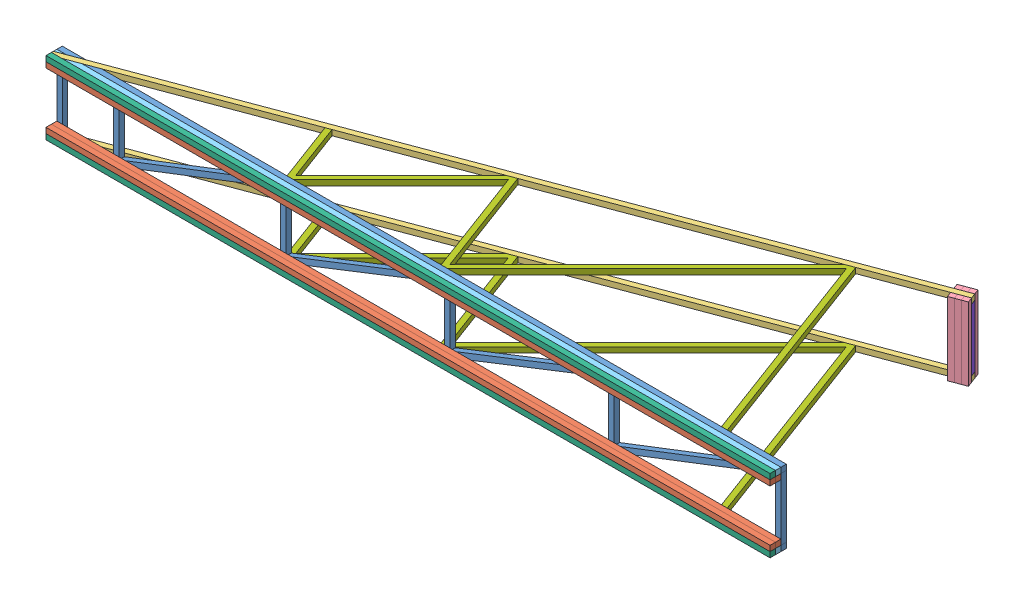
SolidWorks assembly boomAssembly2, configuration Default. Lengths in mm.
Overall size (423.17 42.7 153.75).
20 component instances, 9 part files, 52 mates.
Components (placement in the parent):
- cross brace compression-3: cross brace compression [Default] at (-109.2004 207.2528 347.8228) size (423.18 42.7 3.17)
- Part1-1: Part1 [Default] at (-109.2004 207.2528 354.1728) size (423.18 36.35 3.17)
- tension members-3: tension members [Default] at (269.1249 227.7278 350.9978) x (-1 0 0) z (0 0 1) size (393.21 3.18 147.6)
- tension members-4: tension members [Default] at (269.1249 267.2528 350.9978) x (-1 0 0) z (0 0 1) size (393.21 3.18 147.6)
- jHookMount-1: jHookMount [Default] at (261.7444 215.9028 210.8607) x (0.936777 0 -0.349926) z (0 1 0) size (3.17 3.17 42.7)
- jHookMount-2: jHookMount [Default] at (263.9664 215.9028 216.8092) x (0.936777 0 -0.349926) z (0 1 0) size (3.17 3.17 42.7)
- Part1^boomAssembly2-1: Part1^boomAssembly2 [Default] at origin (virtual)
- Part2^boomAssembly2-1: Part2^boomAssembly2 [Default] at (269.1249 258.6028 350.9978) x (1 0 0) z (0 1 0) size (423.17 3.17 3.17) (virtual)
- Part1-2: Part1 [Default] at (-109.2004 207.2528 357.3478) size (423.18 36.35 3.17)
- Part3^boomAssembly2-1: Part3^boomAssembly2 [Default] at (-127.3754 207.2528 357.3478) x (0 0 1) z (-1 0 0) size (3.17 42.7 423.18) (virtual)
- Part4^boomAssembly2-1: Part4^boomAssembly2 [Default] at (269.1249 258.6028 350.9978) x (1 0 0) z (0 1 0) size (270.59 119.85 3.17) (virtual)
- Part2^boomAssembly2-2: Part2^boomAssembly2 [Default] at (269.1249 219.0778 350.9978) x (1 0 0) z (0 1 0) size (423.17 3.17 3.17) (virtual)
- Part4^boomAssembly2-2: Part4^boomAssembly2 [Default] at (269.1249 219.0778 350.9978) x (1 0 0) z (0 1 0) size (270.59 119.85 3.17) (virtual)
- jHookMount-8: jHookMount [Default] at (258.7701 215.9028 211.9717) x (0.936777 0 -0.349926) z (0 1 0) size (3.17 3.17 42.7)
- jHookMount-9: jHookMount [Default] at (262.8554 215.9028 213.835) x (-0.936777 0 0.349926) z (0 1 0) size (3.17 3.17 42.7)
- jHookMount-10: jHookMount [Default] at (255.7958 215.9028 213.0827) x (0.936777 0 -0.349926) z (0 1 0) size (3.17 3.17 42.7)
- jHookMount-11: jHookMount [Default] at (258.0179 215.9028 219.0313) x (0.936777 0 -0.349926) z (0 1 0) size (3.17 3.17 42.7)
- Part5^boomAssembly2-1: Part5^boomAssembly2 [Default] at (264.7186 215.9028 209.7497) x (0 -1 0) z (0.936777 0 -0.349926) size (36.35 3.17 3.17) (virtual)
- Part5^boomAssembly2-2: Part5^boomAssembly2 [Default] at (261.7444 215.9028 210.8607) x (0 -1 0) z (0.936777 0 -0.349926) size (36.35 3.17 3.17) (virtual)
- Part5^boomAssembly2-3: Part5^boomAssembly2 [Default] at (258.7701 215.9028 211.9717) x (0 -1 0) z (0.936777 0 -0.349926) size (36.35 3.17 3.17) (virtual)
Mates (geometry in assembly coordinates):
- Coincident4: coincident: plane of cross brace compression-3 through (-127.3754 207.2528 350.9978) normal (-1 0 0); plane of Part1-1 through (-127.3754 207.2528 357.3478) normal (-1 0 0)
- Coincident5: coincident: plane of cross brace compression-3 through (-109.2004 207.2528 354.1728) normal (0 0 1); plane of Part1-1 through (-109.2004 207.2528 354.1728) normal (0 0 -1)
- Coincident7: coincident: plane of Part1-1 through (-109.2004 207.2528 357.3478) normal (0 0 1); plane of tension members-3 through (291.79 227.7278 357.3478) normal (0 0 1)
- Coincident8: coincident: plane of cross brace compression-3 through (-107.5644 219.0778 352.2026) normal (-0.349926 0 -0.936777); plane of tension members-3 through (223.3948 176.3778 228.5752) normal (0.349926 0 0.936777)
- Coincident9: coincident: plane of Part1-1 through (-109.2004 219.0778 357.3478) normal (0 -1 0); plane of tension members-3 through (291.79 219.0778 350.9978) normal (0 1 0)
- Coincident10: coincident: plane of cross brace compression-3 through (-108.6754 255.4278 349.2284) normal (0.349926 0 0.936777); plane of tension members-4 through (222.2837 215.9028 225.6009) normal (-0.349926 0 -0.936777)
- Coincident11: coincident: plane of Part1-1 through (-109.2004 207.2528 357.3478) normal (0 0 1); plane of tension members-4 through (291.79 267.2528 357.3478) normal (0 0 1)
- Coincident12: coincident: plane of cross brace compression-3 through (-131.8656 258.6028 347.8228) normal (0 1 0); plane of tension members-4 through (291.79 258.6028 350.9978) normal (0 1 0)
- Coincident13: coincident: plane of cross brace compression-3 through (-131.8656 219.0778 347.8228) normal (0 1 0); plane of Part1-1 through (-109.2004 219.0778 357.3478) normal (0 -1 0)
- Coincident14: coincident: plane of tension members-3 through (222.2837 176.3778 225.6009) normal (-0.349926 0 -0.936777); plane of jHookMount-1 through (261.7444 258.6028 210.8607) normal (0.349926 0 0.936777)
- Coincident15: coincident: plane of tension members-4 through (291.79 258.6028 350.9978) normal (0 1 0); plane of jHookMount-1 through (261.7444 258.6028 210.8607) normal (0 1 0)
- Coincident17: coincident: plane of tension members-3 through (223.3948 176.3778 228.5752) normal (0.349926 0 0.936777); plane of jHookMount-2 through (262.8554 258.6028 213.835) normal (-0.349926 0 -0.936777)
- Coincident19: coincident: plane of tension members-3 through (291.79 215.9028 350.9978) normal (0 -1 0); plane of jHookMount-2 through (263.9664 215.9028 216.8092) normal (0 -1 0)
- InPlace1: in place: plane of tension members-4 through (291.79 258.6028 350.9978) normal (0 1 0); plane of ? through (0 258.6028 0) normal (0 1 0); moOrthogonalPlaneRef_w of tension members-4 through (291.79 258.6028 350.9978) normal (0 1 0); plane of ? through (0 258.6028 0) normal (0 0 -1); plane of tension members-4 through (291.79 258.6028 350.9978) normal (0 1 0); plane of ? through (0 258.6028 0) normal (1 0 0); plane of tension members-4 through (291.79 258.6028 350.9978) normal (0 1 0); unknown of ?
- Coincident20: coincident: plane of tension members-4; plane of Part2^boomAssembly2-1
- Coincident21: coincident: moOrthogonalPlaneRef_w of tension members-4 through (269.1249 258.6028 350.9978) normal (0 0 -1); plane of Part2^boomAssembly2-1 through (269.1249 258.6028 350.9978) normal (0 0 -1)
- Coincident22: coincident: moOrthogonalPlaneRef_w of tension members-4 through (269.1249 258.6028 350.9978) normal (-1 0 0); plane of Part2^boomAssembly2-1 through (269.1249 258.6028 350.9978) normal (1 0 0)
- Coincident23: coincident: plane of Part1-1 through (-109.2004 222.2528 357.3478) normal (0 1 0); plane of Part1-2 through (-109.2004 222.2528 360.5228) normal (0 1 0)
- Coincident24: coincident: plane of Part1-1 through (-109.2004 207.2528 357.3478) normal (0 0 1); plane of Part1-2 through (-109.2004 207.2528 357.3478) normal (0 0 -1)
- Coincident25: coincident: plane of cross brace compression-3 through (-127.3754 207.2528 350.9978) normal (-1 0 0); plane of Part1-2 through (-127.3754 207.2528 360.5228) normal (-1 0 0)
- InPlace2: in place: plane of Part1-2 through (-127.3754 207.2528 360.5228) normal (-1 0 0); plane of ? through (-127.3754 0 0) normal (-1 0 0); plane of Part1-2 through (-127.3754 207.2528 360.5228) normal (-1 0 0); plane of ? through (-127.3754 0 0) normal (0 1 0); plane of Part1-2 through (-127.3754 207.2528 360.5228) normal (-1 0 0); plane of ? through (-127.3754 0 0) normal (0 0 1); plane of Part1-2 through (-127.3754 207.2528 360.5228) normal (-1 0 0); unknown of Part3^boomAssembly2-1
- Coincident26: coincident: plane of Part1-2; plane of Part3^boomAssembly2-1
- Coincident27: coincident: moOrthogonalPlaneRef_w of Part1-2 through (-127.3754 207.2528 357.3478) normal (0 1 0); plane of Part3^boomAssembly2-1 through (-127.3754 207.2528 357.3478) normal (0 1 0)
- Coincident28: coincident: moOrthogonalPlaneRef_w of Part1-2 through (-127.3754 207.2528 357.3478) normal (0 0 -1); plane of Part3^boomAssembly2-1 through (-127.3754 207.2528 357.3478) normal (0 0 1)
- InPlace3: in place: plane of tension members-4 through (291.79 258.6028 350.9978) normal (0 1 0); plane of ? through (0 258.6028 0) normal (0 1 0); plane of tension members-4 through (291.79 258.6028 350.9978) normal (0 1 0); plane of ? through (0 258.6028 0) normal (0 0 -1); plane of tension members-4 through (291.79 258.6028 350.9978) normal (0 1 0); plane of ? through (0 258.6028 0) normal (1 0 0); plane of tension members-4 through (291.79 258.6028 350.9978) normal (0 1 0); unknown of ?
- Coincident29: coincident: plane of tension members-4; plane of Part4^boomAssembly2-1
- Coincident30: coincident: moOrthogonalPlaneRef_w of tension members-4 through (269.1249 258.6028 350.9978) normal (0 0 -1); plane of Part4^boomAssembly2-1 through (269.1249 258.6028 350.9978) normal (0 0 -1)
- Coincident31: coincident: moOrthogonalPlaneRef_w of tension members-4 through (269.1249 258.6028 350.9978) normal (-1 0 0); plane of Part4^boomAssembly2-1 through (269.1249 258.6028 350.9978) normal (1 0 0)
- Coincident32: coincident: plane of tension members-4 through (311.5597 267.2528 335.1466) normal (0.936777 0 -0.349926); plane of jHookMount-1 through (264.7186 258.6028 209.7497) normal (0.936777 0 -0.349926)
- Coincident33: coincident: plane of tension members-4 through (311.5597 267.2528 335.1466) normal (0.936777 0 -0.349926); plane of jHookMount-2 through (266.9407 258.6028 215.6982) normal (0.936777 0 -0.349926)
- Coincident34: coincident: plane of tension members-4 through (223.3948 215.9028 228.5752) normal (0.349926 0 0.936777); plane of jHookMount-11 through (256.9068 258.6028 216.057) normal (-0.349926 0 -0.936777)
- Coincident35: coincident: plane of tension members-4 through (223.3948 215.9028 228.5752) normal (0.349926 0 0.936777); plane of jHookMount-9 through (262.8554 258.6028 213.835) normal (-0.349926 0 -0.936777)
- Coincident36: coincident: plane of tension members-3 through (291.79 215.9028 350.9978) normal (0 -1 0); plane of jHookMount-9 through (262.8554 215.9028 213.835) normal (0 -1 0)
- Coincident37: coincident: plane of tension members-3 through (291.79 215.9028 350.9978) normal (0 -1 0); plane of jHookMount-11 through (258.0179 215.9028 219.0313) normal (0 -1 0)
- Coincident38: coincident: plane of tension members-3 through (222.2837 176.3778 225.6009) normal (-0.349926 0 -0.936777); plane of jHookMount-8 through (258.7701 258.6028 211.9717) normal (0.349926 0 0.936777)
- Coincident39: coincident: plane of tension members-3 through (222.2837 176.3778 225.6009) normal (-0.349926 0 -0.936777); plane of jHookMount-10 through (255.7958 258.6028 213.0827) normal (0.349926 0 0.936777)
- Coincident40: coincident: plane of tension members-3 through (291.79 215.9028 350.9978) normal (0 -1 0); plane of jHookMount-8 through (258.7701 215.9028 211.9717) normal (0 -1 0)
- Coincident41: coincident: plane of tension members-3 through (291.79 215.9028 350.9978) normal (0 -1 0); plane of jHookMount-10 through (255.7958 215.9028 213.0827) normal (0 -1 0)
- Coincident42: coincident: plane of jHookMount-1 through (261.7444 258.6028 210.8607) normal (-0.936777 0 0.349926); plane of jHookMount-8 through (261.7444 258.6028 210.8607) normal (0.936777 0 -0.349926)
- Coincident43: coincident: plane of jHookMount-8 through (258.7701 258.6028 211.9717) normal (-0.936777 0 0.349926); plane of jHookMount-10 through (258.7701 258.6028 211.9717) normal (0.936777 0 -0.349926)
- Coincident44: coincident: plane of jHookMount-2 through (263.9664 258.6028 216.8092) normal (-0.936777 0 0.349926); plane of jHookMount-9 through (262.8554 258.6028 213.835) normal (0.936777 0 -0.349926)
- Coincident45: coincident: plane of jHookMount-9 through (259.8811 258.6028 214.946) normal (-0.936777 0 0.349926); plane of jHookMount-11 through (260.9921 258.6028 217.9203) normal (0.936777 0 -0.349926)
- InPlace4: in place: plane of jHookMount-1 through (264.7186 258.6028 209.7497) normal (0.936777 0 -0.349926); plane of ? through (163.5476 0 -61.092) normal (0.936777 0 -0.349926); plane of jHookMount-1 through (264.7186 258.6028 209.7497) normal (0.936777 0 -0.349926); plane of ? through (163.5476 0 -61.092) normal (0 1 0); plane of jHookMount-1 through (264.7186 258.6028 209.7497) normal (0.936777 0 -0.349926); plane of ? through (163.5476 0 -61.092) normal (-0.349926 0 -0.936777); plane of jHookMount-1 through (264.7186 258.6028 209.7497) normal (0.936777 0 -0.349926); unknown of Part5^boomAssembly2-1
- Coincident46: coincident: plane of jHookMount-1; plane of Part5^boomAssembly2-1
- Coincident47: coincident: moOrthogonalPlaneRef_w of jHookMount-1 through (264.7186 215.9028 209.7497) normal (-0.349926 0 -0.936777); plane of Part5^boomAssembly2-1 through (264.7186 215.9028 209.7497) normal (-0.349926 0 -0.936777)
- Coincident48: coincident: moOrthogonalPlaneRef_w of jHookMount-1 through (264.7186 215.9028 209.7497) normal (0 1 0); plane of Part5^boomAssembly2-1 through (264.7186 215.9028 209.7497) normal (0 -1 0)
- Coincident49: coincident: plane of tension members-4 through (291.79 255.4278 350.9978) normal (0 -1 0); plane of Part5^boomAssembly2-2 through (258.7701 255.4278 211.9717) normal (0 1 0)
- Coincident50: coincident: plane of Part5^boomAssembly2-1 through (261.7444 215.9028 210.8607) normal (-0.936777 0 0.349926); plane of Part5^boomAssembly2-2 through (261.7444 215.9028 210.8607) normal (0.936777 0 -0.349926)
- Coincident51: coincident: plane of jHookMount-8 through (258.7701 258.6028 211.9717) normal (0.349926 0 0.936777); plane of Part5^boomAssembly2-2 through (258.7701 255.4278 211.9717) normal (-0.349926 0 -0.936777)
- Coincident52: coincident: plane of jHookMount-10 through (255.7958 258.6028 213.0827) normal (0.349926 0 0.936777); plane of Part5^boomAssembly2-3 through (255.7958 255.4278 213.0827) normal (-0.349926 0 -0.936777)
- Coincident53: coincident: plane of tension members-4 through (291.79 255.4278 350.9978) normal (0 -1 0); plane of Part5^boomAssembly2-3 through (255.7958 255.4278 213.0827) normal (0 1 0)
- Coincident54: coincident: plane of Part5^boomAssembly2-2 through (258.7701 215.9028 211.9717) normal (-0.936777 0 0.349926); plane of Part5^boomAssembly2-3 through (258.7701 215.9028 211.9717) normal (0.936777 0 -0.349926)
